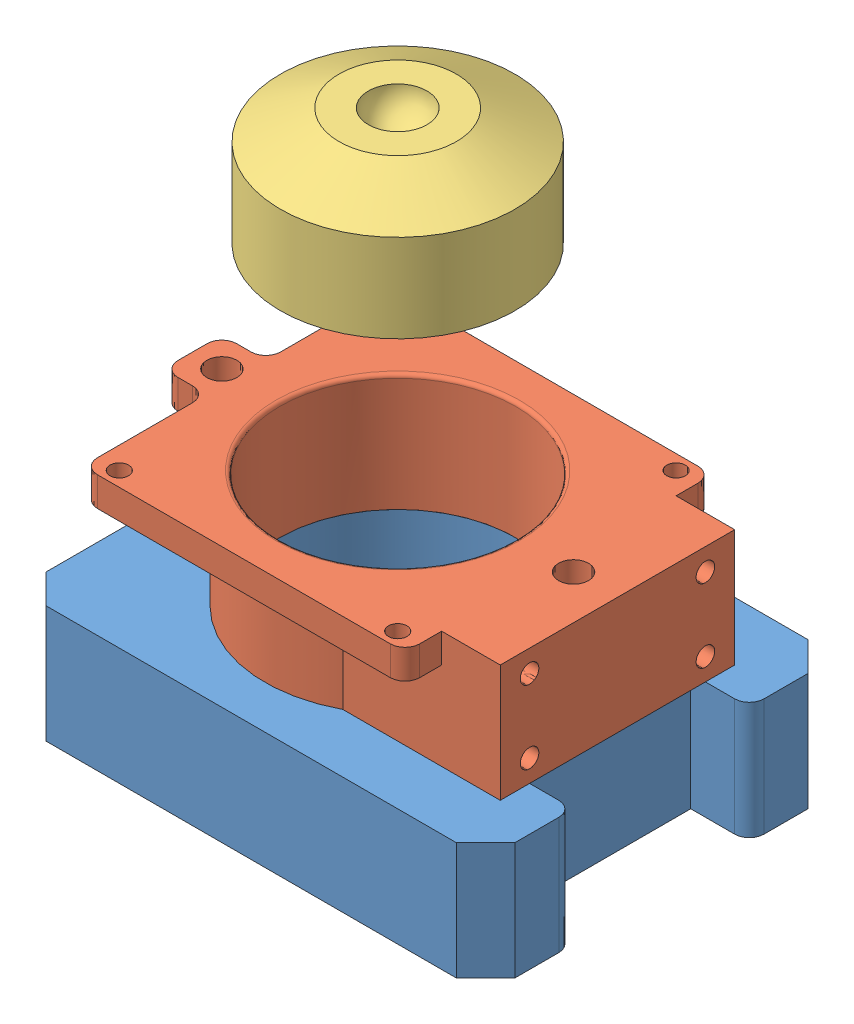
SolidWorks assembly Assem1, configuration Default. Lengths in mm.
Overall size (101.6 118.85 76.2).
3 component instances, 3 part files, 3 mates.
Components (placement in the parent):
- 2in_shear_box_base-1: 2in_shear_box_base [Default] at origin size (101.6 25.4 76.2)
- 2in_sample_top_plate-1: 2in_sample_top_plate [Default] at (-6.35 25.4 0) x (0 0 -1) z (1 0 0) size (66.67 25.4 92.08)
- normal_puck-1: normal_puck [Default] at (-6.35 93.4474 0) x (0.806437 0 0.59132) z (-0.59132 0 0.806437) size (50.8 25.4 50.8)
Mates (geometry in assembly coordinates):
- Concentric3: concentric aligned: cylinder of 2in_shear_box_base-1 through (-6.35 12.7 0) axis (0 1 0) radius 25.5905; cylinder of 2in_sample_top_plate-1 through (-6.35 25.4 0) axis (0 1 0) radius 25.5905
- Coincident3: coincident anti-aligned: plane of 2in_shear_box_base-1 through (0 25.4 0) normal (0 1 0); plane of 2in_sample_top_plate-1 through (-6.35 25.4 0) normal (0 -1 0)
- Concentric4: concentric anti-aligned: cylinder of 2in_sample_top_plate-1 through (-6.35 25.4 0) axis (0 1 0) radius 25.5905; cylinder of normal_puck-1 through (-6.35 93.4474 0) axis (0 -1 0) radius 25.4
